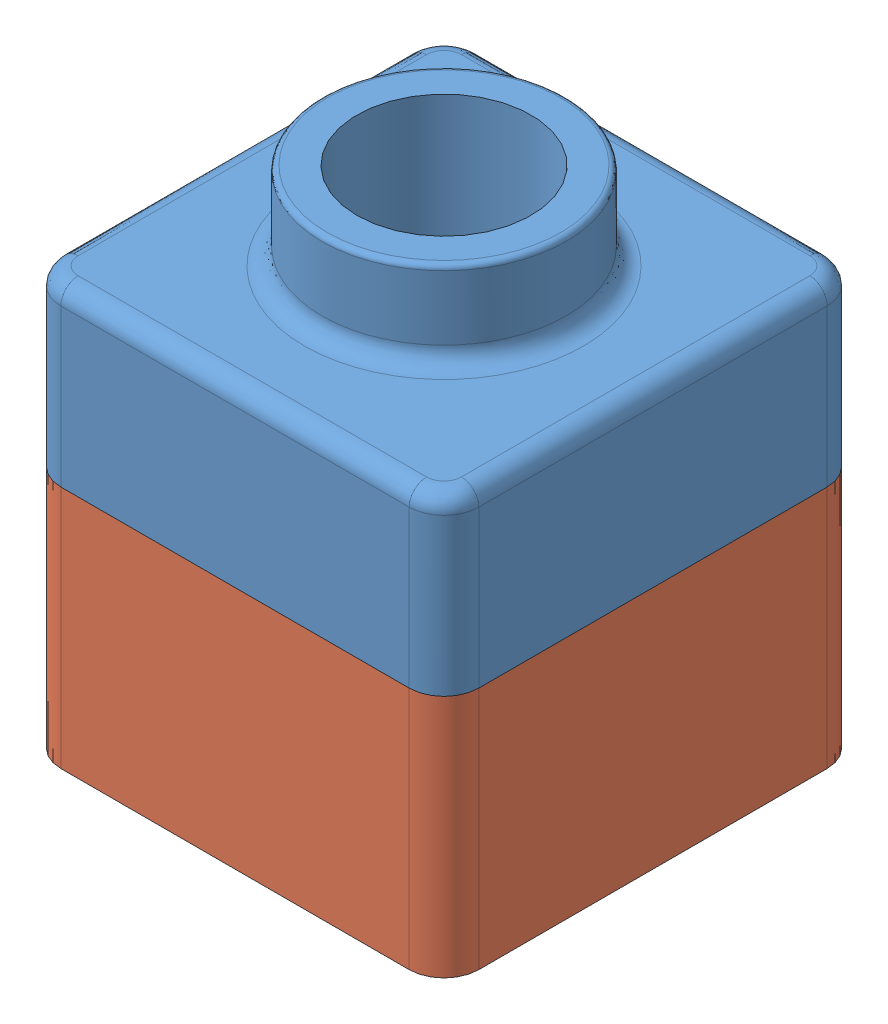
SolidWorks assembly tutor.asmb, configuration Default. Lengths in mm.
Overall size (120 145 120).
2 component instances, 2 part files, 2 mates.
Components (placement in the parent):
- tutor1-1: tutor1 [Default] at (49.109 48.5504 99.3931) size (120 75 120)
- tutor2-1: tutor2 [Default] at (1.4894 68.5504 60.2305) x (1 0 0) z (0 -1 0) size (120 120 90)
Mates (geometry in assembly coordinates):
- Coincident1: coincident: line of tutor1-1 through (11.4894 48.5504 60.2305) axis (1 0 0); line of tutor2-1 through (111.4894 48.5504 60.2305) axis (-1 0 0)
- Coincident2: coincident anti-aligned: line of tutor1-1 through (121.4894 48.5504 70.2305) axis (0 0 1); line of tutor2-1 through (121.4894 48.5504 170.2305) axis (0 0 -1)
